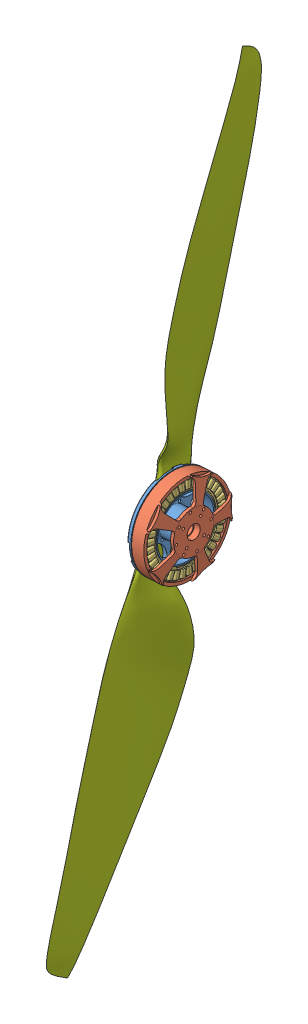
SolidWorks assembly Assem8, configuration Default. Lengths in mm.
Overall size (64.94 703.19 272.74).
11 component instances, 7 part files, 5 mates.
Components (placement in the parent):
- ASM000_TMOTOR_U8-1: ASM000_TMOTOR_U8 [Default] at (-1076.4207 322.71 1730.4517) x (-0.041634 0.794416 -0.605945) z (0.031713 -0.605115 -0.795507) size (88.66 26.69 87.17)
  - 020_U8_STATOR_HOUSING-1: 020_U8_STATOR_HOUSING [Default] at origin size (86.8 18.69 86.8)
  - 010_U8_ROTOR-1: 010_U8_ROTOR [Default] at origin size (88.66 24.5 87.17)
  - 021_U8_STATOR_COILS-1: 021_U8_STATOR_COILS [Default] at (0 -12.5 0) size (81 11.5 81)
  - 5972K155_BALL BEARING-1: 5972K155_BALL BEARING [5972K155] at (0 -10.5 0) x (1 0 0) z (0 -1 0) size (24 24 5)
  - 5972K155_BALL BEARING-2: 5972K155_BALL BEARING [5972K155] at (0 -22 0) x (1 0 0) z (0 -1 0) size (24 24 5)
  - 011_U8_ROTOR_CAP-1: 011_U8_ROTOR_CAP [Default] at (0 -24.5 0) x (1 0 0) z (0 0 -1) size (18.5 2 18.5)
  - 91294A128_BLACK ALLOY STEEL FLAT-HEAD SOCKET CAP SCREW-1: 91294A128_BLACK ALLOY STEEL FLAT-HEAD SOCKET CAP SCREW [91294A128] at (0 -26.5 5.5) x (1 0 0) z (0 -1 0) size (6 6 8.29)
  - 91294A128_BLACK ALLOY STEEL FLAT-HEAD SOCKET CAP SCREW-2: 91294A128_BLACK ALLOY STEEL FLAT-HEAD SOCKET CAP SCREW [91294A128] at (0 -26.5 -5.5) x (0.999066 0 -0.043219) z (0 -1 0) size (6 6 8.29)
- 28in Propellar Blade Half-1: 28in Propellar Blade Half [Default] at (-1105.8296 318.6252 1723.1608) x (-0.049422 0.943037 -0.328997) z (-0.017218 0.328546 0.944331) size (355.78 28.24 68.37)
- 28in Propellar Blade Half-2: 28in Propellar Blade Half [Default] at (-1106.1347 323.6963 1737.7426) x (0.049422 -0.943037 0.328997) z (0.017218 -0.328546 -0.944331) size (355.78 28.24 68.37)
Mates (geometry in assembly coordinates):
- Coincident1: coincident anti-aligned: plane of 28in Propellar Blade Half-1 through (-1105.8296 318.6252 1723.1608) normal (0.049422 -0.943037 0.328997); plane of 28in Propellar Blade Half-2 through (-1106.1347 323.6963 1737.7426) normal (-0.049422 0.943037 -0.328997)
- Concentric1: concentric aligned: cylinder of 28in Propellar Blade Half-1 through (-1100.9693 321.4235 1730.4517) axis (-0.99863 -0.052336 0) radius 5; cylinder of 28in Propellar Blade Half-2 through (-1101.0086 321.4214 1730.4517) axis (-0.99863 -0.052336 0) radius 5
- Concentric2: concentric anti-aligned: cylinder of ASM000_TMOTOR_U8-1/011_U8_ROTOR_CAP-1 through (-1102.8844 321.3231 1730.4517) axis (0.99863 0.052336 0) radius 2; cylinder of 28in Propellar Blade Half-1 through (-1100.9693 321.4235 1730.4517) axis (-0.99863 -0.052336 0) radius 5
- Tangent1: tangent anti-aligned: plane of ? through (-1103.384 330.8561 1723.1803) normal (-0.99863 -0.052336 0); face of 28in Propellar Blade Half-2
- Tangent2: tangent anti-aligned: plane of ASM000_TMOTOR_U8-1/011_U8_ROTOR_CAP-1 through (-1102.8844 321.3231 1730.4517) normal (-0.99863 -0.052336 0); edge_curve of 28in Propellar Blade Half-1
